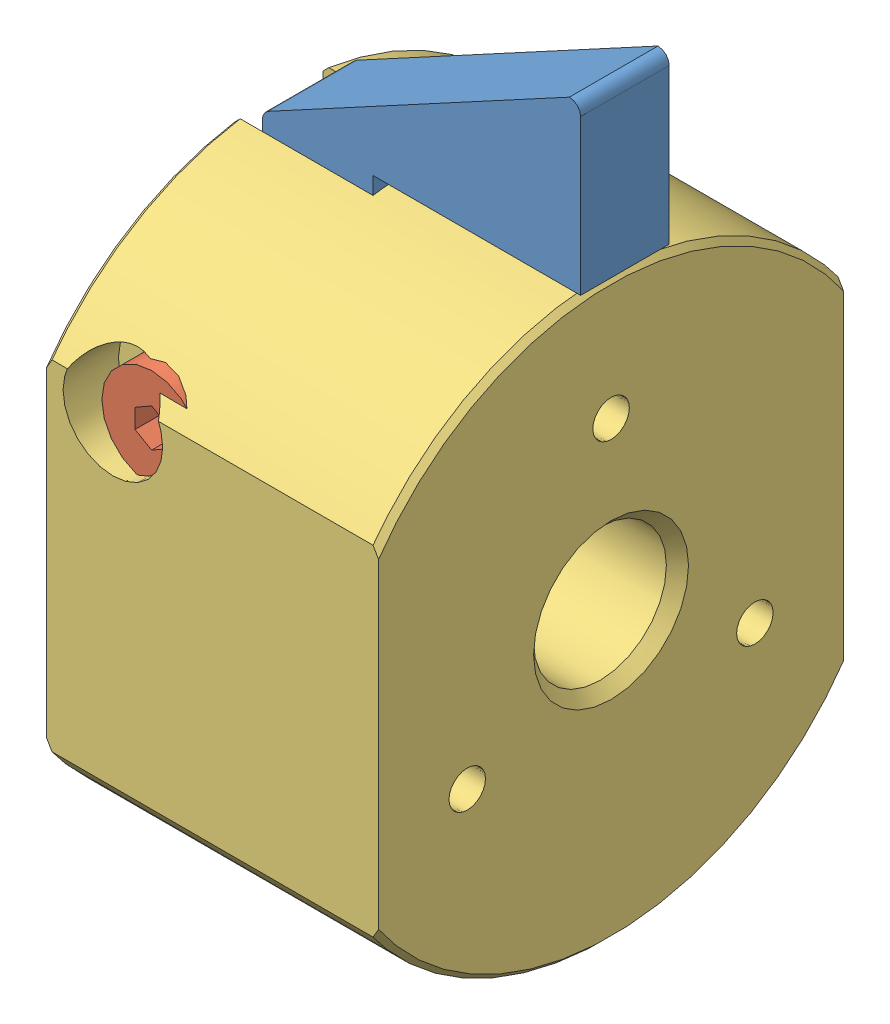
SolidWorks assembly WSC12, configuration Default. Lengths in mm.
Overall size (31.25 68.25 42.44).
4 component instances, 4 part files, 2 mates.
Components (placement in the parent):
- _WSC12l_4-1: _WSC12l_4 [Default] at (-30 0 0) size (28.75 36.25 8)
- _WSCbl_6-1: _WSCbl_6 [Default] at (-24 13.5 16) x (0 0 -1) z (-1 0 0) size (30.99 9 9)
- Part15^WSC12-1: Part15^WSC12 [Default] at origin (virtual)
- Part14-1: Part14 [Default] at (-2.5009 0 0) size (30 52 42.44)
Mates (geometry in assembly coordinates):
- Concentric2: concentric: cone of _WSC12l_4-1 through (477.62 21.2727 0) axis (-1 0 0); circle of Part14-1
- Coincident6: coincident anti-aligned: plane of _WSC12l_4-1 through (-20.0009 12.096 4) normal (1 0 0); plane of Part14-1 through (-20.0009 0 0) normal (-1 0 0)
